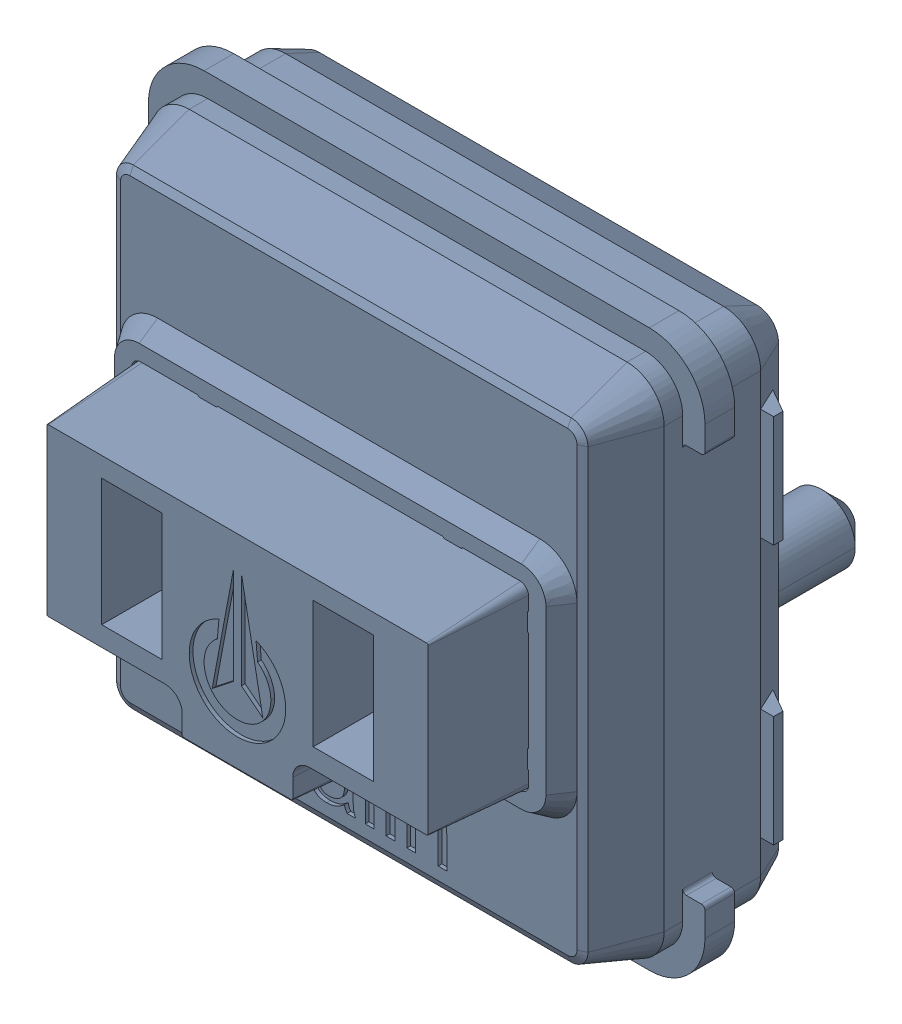
SolidWorks assembly SW5_1.step, configuration Default. Lengths in mm.
Overall size (15 15 11.1).
2 component instances, 2 part files, 0 mates.
Components (placement in the parent):
- Kailh LP Choc Burnt Orange_1.step-11: Kailh LP Choc Burnt Orange_1.step [Default] at (428.7827 226.3933 2.7) x (0 -1 0) z (-1 0 0) size (15 11.1 15)
- WS2812-2020_1.step-11: WS2812-2020_1.step [Default] at (428.8893 231.0345 0.3) x (1 0 0) z (0 -1 0) size (2.2 0.86 2)
